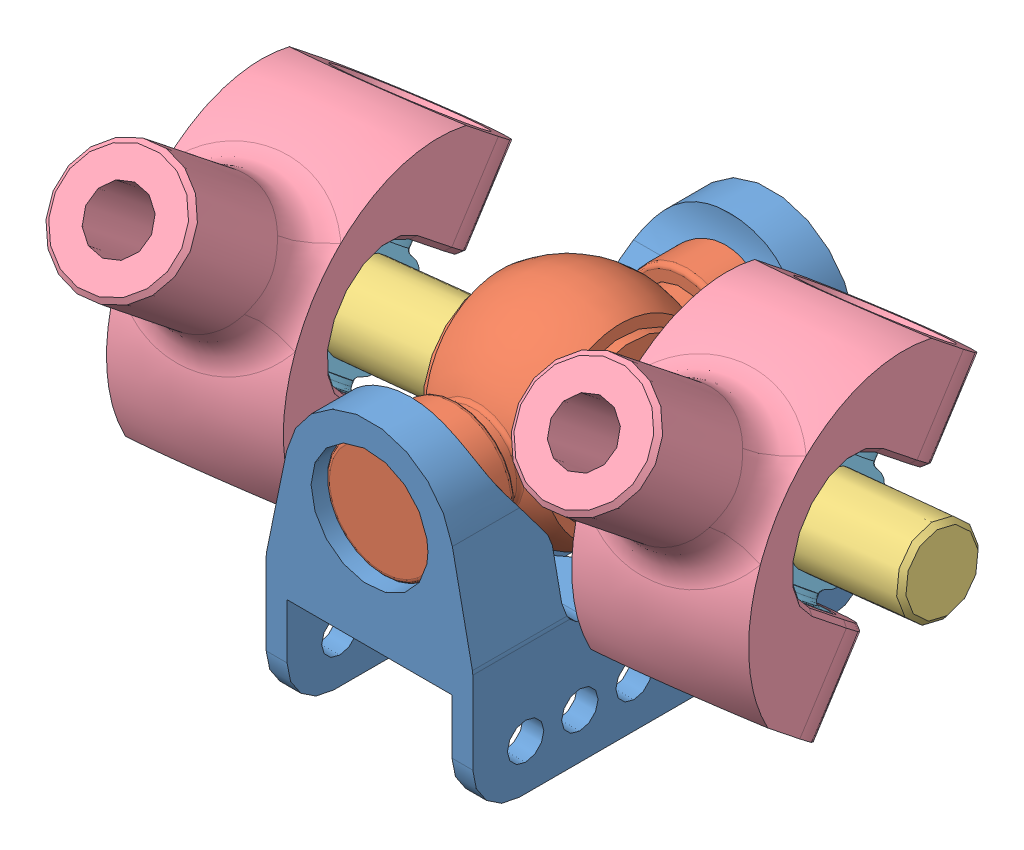
SolidWorks assembly Balance bar, configuration Default. Lengths in mm.
Overall size (102.42 75.33 74.64).
7 component instances, 5 part files, 11 mates.
Components (placement in the parent):
- Balance bar_Mounting-1: Balance bar_Mounting [Default] at (0.5121 11.3466 -2.047) size (28.07 40.45 54.48)
- Balance bar_Spherical-1: Balance bar_Spherical [Default] at (0.5121 11.3466 -2.047) x (0 0 -1) z (0.994648 0.103324 0) size (50.8 28.88 19.05)
- Balance bar_Rod-1: Balance bar_Rod [Default] at (0.5121 11.3466 -2.047) x (0.994648 0.103324 0) z (-0.004346 0.041833 -0.999115) size (101.6 12.7 12.7)
- Balance bar_Clevis-1: Balance bar_Clevis [Default] at (-33.5359 1.178 -10.2223) x (0.080413 -0.774099 0.627937) z (-0.990721 0.007177 0.135719) size (40.64 53.98 21.34)
- Balance bar_Clevis_Spherical-1: Balance bar_Clevis_Spherical [Default] at (-32.367 7.9311 -2.047) x (0.080413 -0.774099 0.627937) z (0.994648 0.103324 0) size (34.92 15.88 15.88)
- Balance bar_Clevis-2: Balance bar_Clevis [Default] at (29.6669 7.7435 -10.2223) x (0.080413 -0.774099 0.627937) z (-0.990721 0.007177 0.135719) size (40.64 53.98 21.34)
- Balance bar_Clevis_Spherical-2: Balance bar_Clevis_Spherical [Default] at (30.8358 14.4966 -2.047) x (0.080413 -0.774099 0.627937) z (0.994648 0.103324 0) size (34.92 15.88 15.88)
Mates (geometry in assembly coordinates):
- Concentric1: concentric anti-aligned: cylinder of Balance bar_Mounting-1 through (0.5121 11.3466 25.1945) axis (0 0 -1) radius 7.9375; cylinder of Balance bar_Spherical-1 through (0.5121 11.3466 38.51) axis (0 0 1) radius 7.9375
- Coincident1: coincident anti-aligned: plane of Balance bar_Mounting-1 through (0.5121 11.3466 -2.047) normal (0 0 1); plane of Balance bar_Spherical-1
- Concentric2: concentric aligned: cylinder of Balance bar_Spherical-1 through (-8.962 10.3624 -2.047) axis (0.994648 0.103324 0) radius 6.35; cylinder of Balance bar_Rod-1 through (-50.016 6.0977 -2.047) axis (0.994648 0.103324 0) radius 6.35
- Coincident2: coincident aligned: plane of Balance bar_Spherical-1 through (0.5121 11.3466 -2.047) normal (0.994648 0.103324 0); plane of Balance bar_Rod-1
- Concentric3: concentric aligned: cylinder of Balance bar_Clevis-1 through (-30.733 -7.7986 10.7127) axis (-0.080413 0.774099 -0.627937) radius 7.9375; cylinder of Balance bar_Clevis_Spherical-1 through (-35.1502 34.7235 -23.7806) axis (-0.080413 0.774099 -0.627937) radius 7.9375
- Coincident3: coincident aligned: plane of Balance bar_Clevis-1; plane of Balance bar_Clevis_Spherical-1
- Concentric4: concentric aligned: cylinder of Balance bar_Clevis-2 through (32.4698 -1.2331 10.7127) axis (-0.080413 0.774099 -0.627937) radius 7.9375; cylinder of Balance bar_Clevis_Spherical-2 through (28.0526 41.289 -23.7806) axis (-0.080413 0.774099 -0.627937) radius 7.9375
- Coincident4: coincident aligned: plane of Balance bar_Clevis-2; plane of Balance bar_Clevis_Spherical-2
- Concentric5: concentric anti-aligned: cylinder of Balance bar_Rod-1 through (-50.016 6.0977 -2.047) axis (0.994648 0.103324 0) radius 5.5563; cylinder of Balance bar_Clevis_Spherical-1 through (-24.472 8.7512 -2.047) axis (-0.994648 -0.103324 0) radius 4.9784
- Concentric6: concentric anti-aligned: cylinder of Balance bar_Rod-1 through (-50.016 6.0977 -2.047) axis (0.994648 0.103324 0) radius 5.5563; cylinder of Balance bar_Clevis_Spherical-2 through (38.7308 15.3167 -2.047) axis (-0.994648 -0.103324 0) radius 4.9784
- Parallel2: parallel aligned: plane of Balance bar_Clevis-1 through (-33.5359 1.178 -10.2223) normal (-0.990721 0.007177 0.135719); plane of Balance bar_Clevis-2 through (29.6669 7.7435 -10.2223) normal (-0.990721 0.007177 0.135719)
